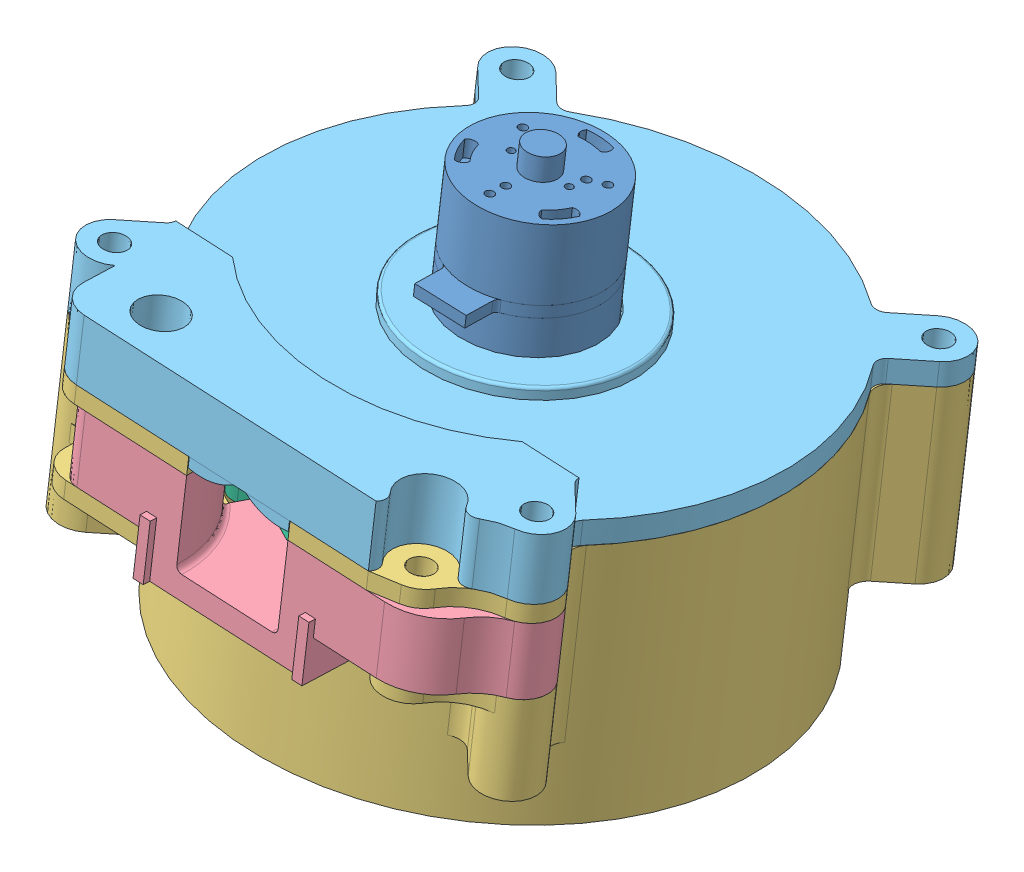
SolidWorks assembly 拨弹模组，上工, configuration 默认. Lengths in mm.
Overall size (100.35 85.69 103.21).
6 component instances, 6 part files, 12 mates.
Components (placement in the parent):
- 新版2006电机(步兵下供弹)IV1.1V1.3-1: 新版2006电机(步兵下供弹)IV1.1V1.3 [默认] at (145.8797 -117.4219 -221.6853) x (-0.123718 -0.957202 0.261647) z (0.055234 0.256621 0.964933) size (64.49 27.18 34.91)
- 轴承30-37-4（步兵下供弹V1.0）IV1.1V1.3-1: 轴承30-37-4（步兵下供弹V1.0）IV1.1V1.3 [默认] at (173.2641 -21.8911 -139.2336) x (0.85725 -0.088252 -0.507281) z (-0.06794 -0.995975 0.058459) size (37 37 4)
- 3D打印-步兵下供弹-弹舱壁上V1.0IV1.1V1.3-1: 3D打印-步兵下供弹-弹舱壁上V1.0IV1.1V1.3 [默认] at (173.8085 -38.0831 -38.132) x (-0.997481 0.069007 0.016423) z (0.06794 0.995975 -0.058459) size (90 96.96 44)
- 3D打印-步兵下供弹-出弹口V1.0IV1.1V1.3-1: 3D打印-步兵下供弹-出弹口V1.0IV1.1V1.3 [默认] at (172.8225 -28.365 -138.8536) x (-0.997481 0.069007 0.016423) z (0.020391 0.057196 0.998155) size (72.5 20.06 33.47)
- 3D打印-步兵下供弹-2006电机套V1.0IV1.1V1.3-2: 3D打印-步兵下供弹-2006电机套V1.0IV1.1V1.3 [默认] at (171.9732 -40.8147 -138.1229) x (0.997481 -0.069007 -0.016423) z (0.020391 0.057195 0.998155) size (90 31 96.96)
- 哨兵拨轮IV1.1V1.3-1: 哨兵拨轮IV1.1V1.3 [默认] at (173.1961 -22.8871 -139.1752) x (-0.53911 -0.012654 -0.84214) z (-0.06794 -0.995975 0.058459) size (70.94 70.91 38)
Mates (geometry in assembly coordinates):
- 重合38: coincident anti-aligned: plane of 3D打印-步兵下供弹-弹舱壁上V1.0IV1.1V1.3-1 through (174.352 -30.1152 -38.5997) normal (0.06794 0.995975 -0.058459); plane of 3D打印-步兵下供弹-出弹口V1.0IV1.1V1.3-1 through (172.3129 -35.8348 -138.4152) normal (-0.06794 -0.995975 0.058459)
- 同心42: concentric aligned: cylinder of 3D打印-步兵下供弹-弹舱壁上V1.0IV1.1V1.3-1 through (199.6991 -35.0377 -93.0075) axis (-0.06794 -0.995975 0.058459) radius 2.15; cylinder of 3D打印-步兵下供弹-出弹口V1.0IV1.1V1.3-1 through (201.2618 -12.1303 -94.352) axis (-0.06794 -0.995975 0.058459) radius 2.05
- 同心43: concentric aligned: cylinder of 3D打印-步兵下供弹-弹舱壁上V1.0IV1.1V1.3-1 through (150.2672 -31.7332 -94.1571) axis (-0.06794 -0.995975 0.058459) radius 2.15; cylinder of 3D打印-步兵下供弹-出弹口V1.0IV1.1V1.3-1 through (151.4902 -13.8057 -95.2093) axis (-0.06794 -0.995975 0.058459) radius 2.05
- 重合42: coincident anti-aligned: plane of 3D打印-步兵下供弹-弹舱壁上V1.0IV1.1V1.3-1 through (187.1668 -18.7941 -87.4165) normal (0.06794 0.995975 -0.058459); plane of 3D打印-步兵下供弹-2006电机套V1.0IV1.1V1.3-2 through (173.332 -20.8952 -139.2921) normal (-0.06794 -0.995975 0.058459)
- 同心47: concentric anti-aligned: cylinder of 3D打印-步兵下供弹-弹舱壁上V1.0IV1.1V1.3-1 through (171.4297 -48.7825 -137.6552) axis (0.06794 0.995975 -0.058459) radius 39; cylinder of 3D打印-步兵下供弹-2006电机套V1.0IV1.1V1.3-2 through (173.332 -20.8952 -139.2921) axis (-0.06794 -0.995975 0.058459) radius 12.5
- 同心48: concentric anti-aligned: cylinder of 3D打印-步兵下供弹-弹舱壁上V1.0IV1.1V1.3-1 through (211.5022 -21.3381 -102.4771) axis (-0.06794 -0.995975 0.058459) radius 2.2; cylinder of 3D打印-步兵下供弹-2006电机套V1.0IV1.1V1.3-2 through (210.1174 -41.6388 -101.2856) axis (0.06794 0.995975 -0.058459) radius 2.2
- 同心49: concentric aligned: cylinder of 新版2006电机(步兵下供弹)IV1.1V1.3-1 through (171.022 -54.7583 -137.3045) axis (-0.06794 -0.995975 0.058459) radius 12.2; cylinder of 3D打印-步兵下供弹-2006电机套V1.0IV1.1V1.3-2 through (173.332 -20.8952 -139.2921) axis (-0.06794 -0.995975 0.058459) radius 12.5
- 重合43: coincident anti-aligned: plane of 新版2006电机(步兵下供弹)IV1.1V1.3-1 through (165.5999 -37.9811 -148.5724) normal (-0.06794 -0.995975 0.058459); plane of 3D打印-步兵下供弹-2006电机套V1.0IV1.1V1.3-2 through (172.177 -37.8267 -138.2983) normal (0.06794 0.995975 -0.058459)
- 同心50: concentric anti-aligned: cylinder of 轴承30-37-4（步兵下供弹V1.0）IV1.1V1.3-1 through (172.9923 -25.875 -138.9998) axis (0.06794 0.995975 -0.058459) radius 15; cylinder of 3D打印-步兵下供弹-2006电机套V1.0IV1.1V1.3-2 through (173.332 -20.8952 -139.2921) axis (-0.06794 -0.995975 0.058459) radius 15
- 重合48: coincident anti-aligned: plane of 轴承30-37-4（步兵下供弹V1.0）IV1.1V1.3-1 through (173.2641 -21.8911 -139.2336) normal (0.06794 0.995975 -0.058459); plane of 3D打印-步兵下供弹-2006电机套V1.0IV1.1V1.3-2 through (173.2641 -21.8911 -139.2336) normal (-0.06794 -0.995975 0.058459)
- 同心51: concentric aligned: cylinder of 新版2006电机(步兵下供弹)IV1.1V1.3-1 through (164.0781 -44.996 -133.0059) axis (0.83949 -0.088731 -0.536081) radius 1.5; cylinder of 哨兵拨轮IV1.1V1.3-1 through (180.0284 -46.6819 -143.1914) axis (0.83949 -0.088731 -0.536081) radius 3
- 同心53: concentric aligned: cylinder of 新版2006电机(步兵下供弹)IV1.1V1.3-1 through (171.022 -54.7583 -137.3045) axis (-0.06794 -0.995975 0.058459) radius 1.25; cylinder of 哨兵拨轮IV1.1V1.3-1 through (173.1961 -22.8871 -139.1752) axis (-0.06794 -0.995975 0.058459) radius 1.5
